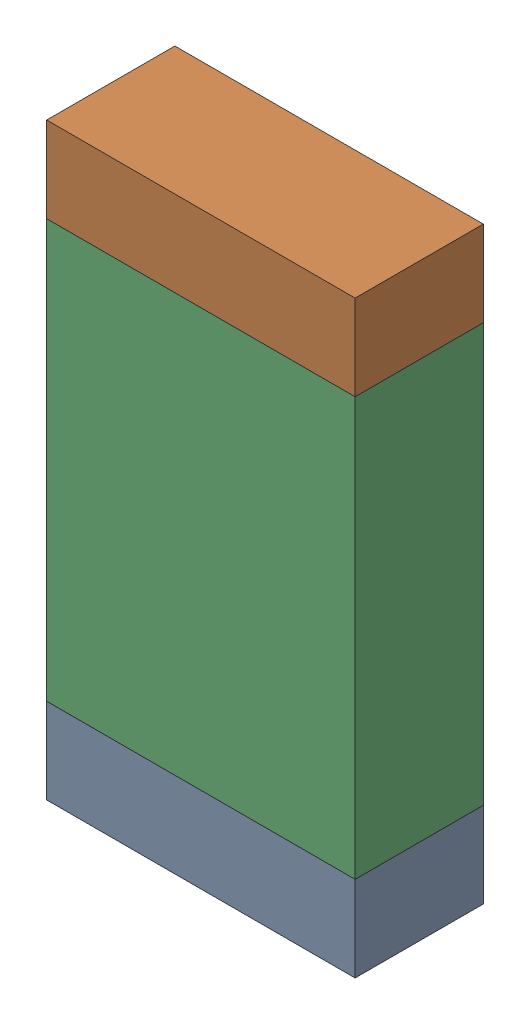
SolidWorks assembly R17, configuration Default. Lengths in mm.
Overall size (0.55 1.05 0.23).
6 component instances, 2 part files, 0 mates.
Components (placement in the parent):
- 822503136-1: 822503136 [Default] at (36.9337 5.5757 0.0254) size (0.55 0.15 0.23)
  - Extruded_13-1: Extruded_13 [Default] at origin size (0.55 0.15 0.23)
- 822503136-2: 822503136 [Default] at (36.9337 6.4732 0.0254) size (0.55 0.15 0.23)
  - Extruded_13-1: Extruded_13 [Default] at origin size (0.55 0.15 0.23)
- 822503272-1: 822503272 [Default] at (36.9337 6.0245 0.0254) size (0.55 0.75 0.23)
  - Extruded_14-1: Extruded_14 [Default] at origin size (0.55 0.75 0.23)
